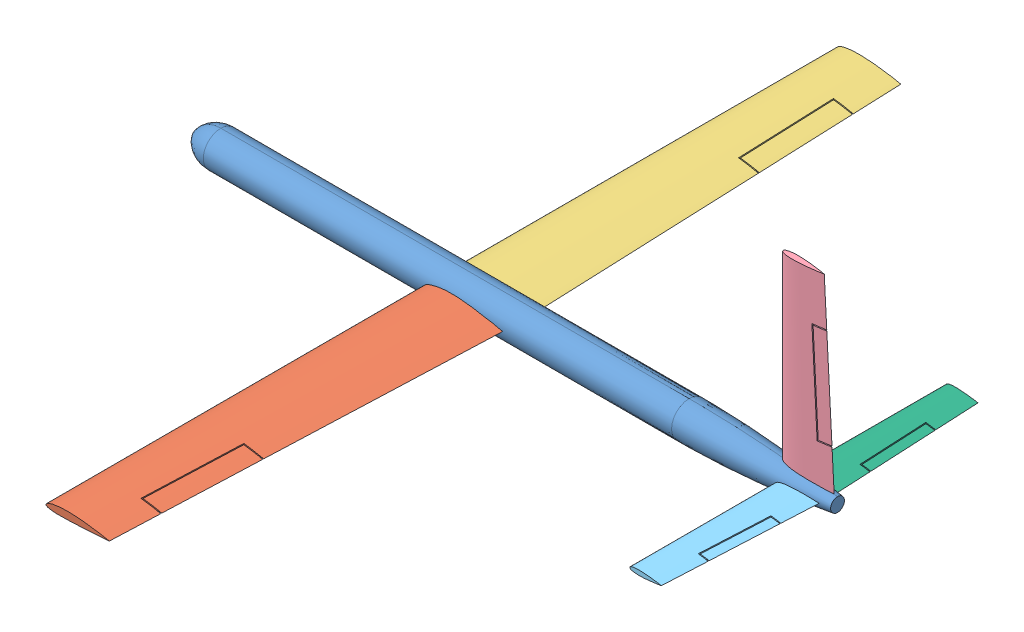
SolidWorks assembly kite_asm_JB, configuration Default. Lengths in mm.
Overall size (6500 2127.8 8000).
7 component instances, 6 part files, 0 mates.
Components (placement in the parent):
- kite_asm.stp-1: kite_asm.stp [Default] at origin size (6500 2127.8 8000)
  - FUSELAGE_CONCEPT.stp-1: FUSELAGE_CONCEPT.stp [Default] at origin size (6500 355.6 355.6)
  - NACA2412_P_4M_0-8C_0S_0D_0-8T.stp-1: NACA2412_P_4M_0-8C_0S_0D_0-8T.stp [Default] at (2500 0 0) size (800.16 97.84 4000)
  - NACA2412_S_4M_0-8C_0S_0D_0-8T.stp-1: NACA2412_S_4M_0-8C_0S_0D_0-8T.stp [Default] at (2500 0 -4000) size (800.04 97.84 4000)
  - NACA0015_1-95M_0-52C_0S_0D_0-8T.stp-1: NACA0015_1-95M_0-52C_0S_0D_0-8T.stp [Default] at (5950 0 0) x (1 0 0) z (0 1 0) size (523.17 78.5 1950.01)
  - NACA0015_1-6M_0-4C_0S_0D_0-8T.stp-1: NACA0015_1-6M_0-4C_0S_0D_0-8T.stp [Default] at (6000 0 0) size (400.06 60.38 1600)
  - STBD_HSTAB.stp-1: STBD_HSTAB.stp [Default] at (6000 0 0) size (400.06 60.38 1600)
